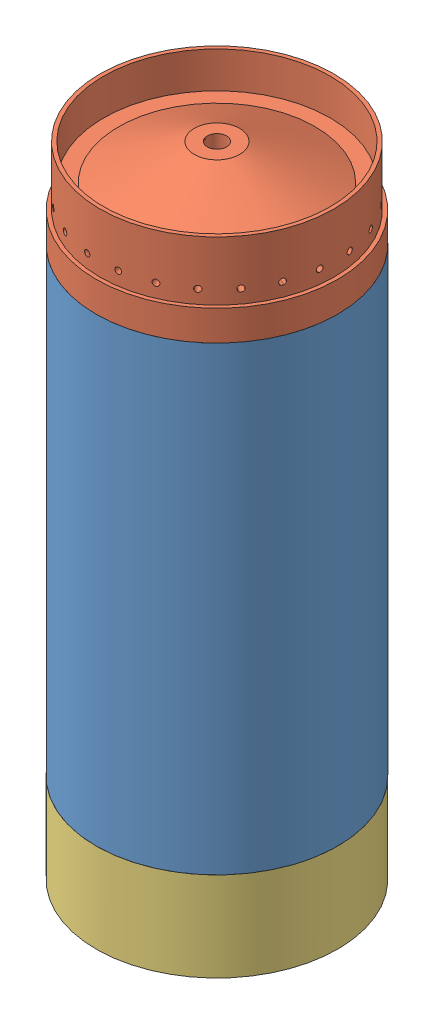
SolidWorks assembly FuelTank, configuration Default. Lengths in mm.
Overall size (287.14 537.53 287.14).
3 component instances, 3 part files, 6 mates.
Components (placement in the parent):
- FuelTankCylinder-1: FuelTankCylinder [Default] at (0 75.0887 0) x (0 1 0) z (-0.969773 0 -0.244009) size (387.35 203.2 203.2)
- IT-B-Bulkhead-1: IT-B-Bulkhead [Default] at (36.4095 499.9831 9.1612) x (0.244009 0 -0.969773) z (0.969773 0 0.244009) size (203.2 75.09 203.2)
- LT-B-BULKHEADv4-1: LT-B-BULKHEADv4 [Default] at (25.4703 37.5444 27.5834) x (-0.734689 0 0.678405) z (0.678405 0 0.734689) size (203.2 75.09 203.2)
Mates (geometry in assembly coordinates):
- Coincident1: coincident anti-aligned: plane of LT-B-BULKHEADv4-1 through (0 0 0) normal (0 -1 0)
- Concentric2: concentric aligned: circle of FuelTankCylinder-1; circle of LT-B-BULKHEADv4-1
- Coincident4: coincident anti-aligned: plane of FuelTankCylinder-1 through (0 75.0887 0) normal (0 -1 0); plane of LT-B-BULKHEADv4-1 through (0 75.0887 0) normal (0 1 0)
- Concentric3: concentric anti-aligned: circle of FuelTankCylinder-1; circle of IT-B-Bulkhead-1
- Coincident6: coincident anti-aligned: plane of FuelTankCylinder-1 through (0 462.4388 0) normal (0 1 0); plane of IT-B-Bulkhead-1 through (0 462.4388 0) normal (0 -1 0)
- Concentric4: concentric aligned: cylinder of LT-B-BULKHEADv4-1 through (0 75.0887 0) axis (0 1 0) radius 8.255
